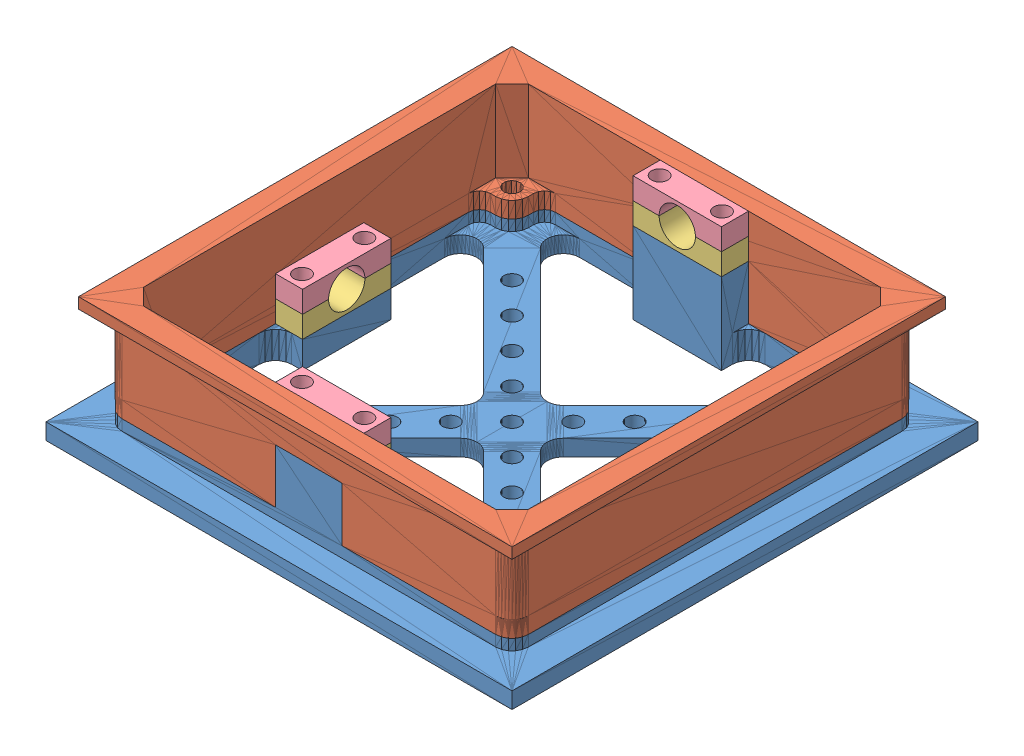
SolidWorks assembly AirCoreAssembly_v9, configuration Default. Lengths in mm.
Overall size (86 23 86).
10 component instances, 4 part files, 23 mates.
Components (placement in the parent):
- Component1_v2-1: Component1_v2 [Default] at (80.9291 -9.2822 -4.7321) x (-1 0 0) z (0 0 1) size (86 15 86)
- Component2_v2-1: Component2_v2 [Default] at (80.9291 -9.2822 -4.7321) x (-1 0 0) z (0 0 1) size (80 18 80)
- RodHatBase-1: RodHatBase [Default] at (37.9291 13.7178 2.7679) x (1 0 0) z (0 0 -1) size (16.31 4.18 5)
- RodHatTop-2: RodHatTop [Default] at (37.9291 17.7178 7.7679) size (16.31 4 5)
- RodHatBase-2: RodHatBase [Default] at (37.9291 13.7178 68.7679) x (1 0 0) z (0 0 -1) size (16.31 4.18 5)
- RodHatBase-3: RodHatBase [Default] at (7.4291 3.7178 38.2679) x (0 0 1) z (1 0 0) size (16.31 4.18 5)
- RodHatBase-4: RodHatBase [Default] at (73.4291 3.7178 38.2679) x (0 0 1) z (1 0 0) size (16.31 4.18 5)
- RodHatTop-3: RodHatTop [Default] at (37.9291 17.7178 73.7679) size (16.31 4 5)
- RodHatTop-4: RodHatTop [Default] at (7.4291 7.7178 38.2679) x (0 0 -1) z (1 0 0) size (16.31 4 5)
- RodHatTop-5: RodHatTop [Default] at (73.4291 7.7178 38.2679) x (0 0 -1) z (1 0 0) size (16.31 4 5)
Mates (geometry in assembly coordinates):
- Coincident2: coincident anti-aligned: plane of Component1_v2-1 through (80.9291 1.7178 -4.7321) normal (0 1 0); plane of Component2_v2-1 through (80.9291 1.7178 -4.7321) normal (0 -1 0)
- Coincident3: coincident anti-aligned: line of Component1_v2-1 through (44.0841 1.7178 0.7679) axis (0 1 0); line of Component2_v2-1 through (44.0841 11.7178 0.7679) axis (0 -1 0)
- Coincident5: coincident aligned: line of Component1_v2-1 through (29.7741 11.7178 7.7679) axis (1 0 0); line of RodHatBase-1 through (29.7741 11.7178 7.7679) axis (1 0 0)
- Coincident6: coincident: point of Component1_v2-1; point of RodHatBase-1
- Coincident7: coincident anti-aligned: plane of Component2_v2-1 through (80.9291 -9.2822 2.7679) normal (0 0 1); plane of RodHatBase-1 through (37.9291 13.7178 2.7679) normal (0 0 -1)
- Coincident9: coincident anti-aligned: line of RodHatBase-1 through (46.0841 15.7178 7.7679) axis (0 0 -1); line of RodHatTop-2 through (46.0841 15.7178 2.7679) axis (0 0 1)
- Coincident10: coincident: point of RodHatBase-1; point of RodHatTop-2
- Concentric1: concentric anti-aligned: circle of RodHatBase-1; circle of RodHatTop-2
- Coincident12: coincident anti-aligned: line of Component2_v2-1 through (70.4291 19.7178 2.7679) axis (-1 0 0); line of RodHatTop-2 through (29.7741 19.7178 2.7679) axis (1 0 0)
- Coincident13: coincident anti-aligned: line of Component1_v2-1 through (46.0841 11.7178 68.7679) axis (-1 0 0); line of RodHatBase-2 through (29.7741 11.7178 68.7679) axis (1 0 0)
- Coincident14: coincident: point of Component1_v2-1; point of RodHatBase-2
- Concentric2: concentric aligned: circle of RodHatBase-1; circle of RodHatBase-2
- Coincident16: coincident anti-aligned: line of Component1_v2-1 through (7.4291 1.7178 46.4229) axis (0 0 -1); line of RodHatBase-3 through (7.4291 1.7178 30.1129) axis (0 0 1)
- Coincident17: coincident: point of Component1_v2-1; point of RodHatBase-3
- Coincident20: coincident: point of Component1_v2-1; point of RodHatBase-4
- Concentric3: concentric aligned: circle of RodHatBase-3; circle of RodHatBase-4
- Coincident22: coincident aligned: line of Component1_v2-1 through (68.4291 1.7178 30.1129) axis (0 0 1); line of RodHatBase-4 through (68.4291 1.7178 30.1129) axis (0 0 1)
- Coincident25: coincident aligned: line of RodHatBase-2 through (41.2841 15.7178 68.7679) axis (1 0 0); line of RodHatTop-3 through (41.2841 15.7178 68.7679) axis (1 0 0)
- Concentric5: concentric anti-aligned: circle of RodHatBase-2; circle of RodHatTop-3
- Concentric6: concentric aligned: circle of RodHatBase-3; circle of RodHatTop-4
- Coincident28: coincident anti-aligned: line of RodHatBase-3 through (7.4291 5.7178 30.1129) axis (0 0 1); line of RodHatTop-4 through (7.4291 5.7178 34.9129) axis (0 0 -1)
- Coincident29: coincident anti-aligned: line of RodHatBase-4 through (68.4291 5.7178 41.6229) axis (0 0 1); line of RodHatTop-5 through (68.4291 5.7178 46.4229) axis (0 0 -1)
- Concentric7: concentric aligned: circle of RodHatBase-3; circle of RodHatTop-5
